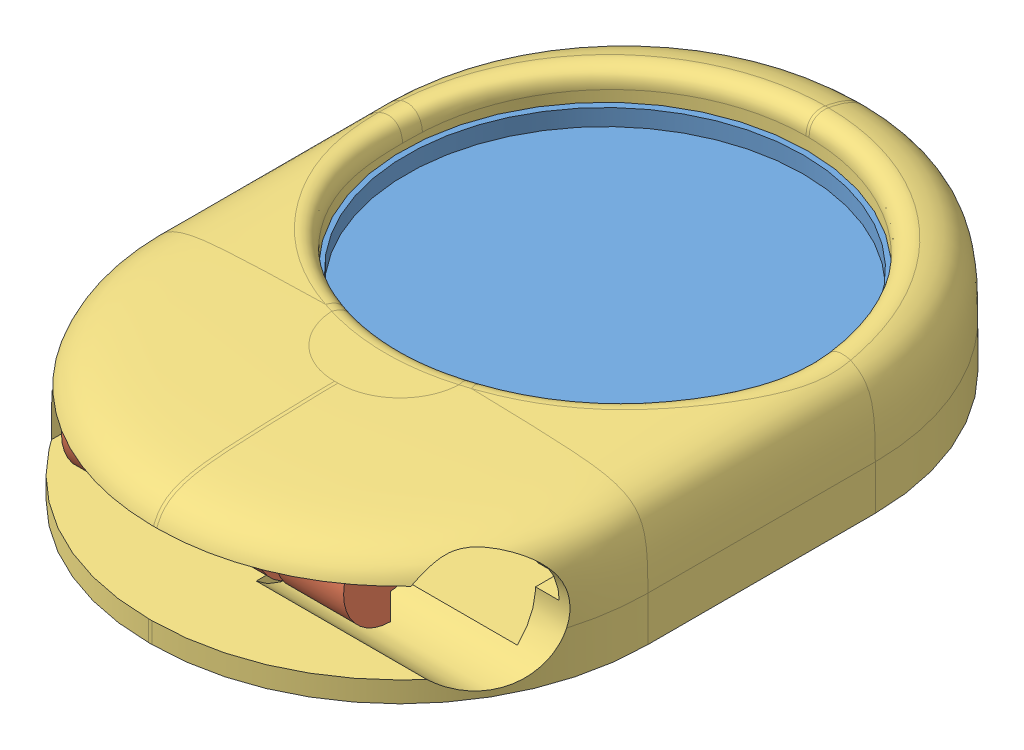
SolidWorks assembly Vibe and speaker enclosure, configuration Default. Lengths in mm.
Overall size (30.69 8.21 44.45).
3 component instances, 3 part files, 5 mates.
Components (placement in the parent):
- Speaker-1: Speaker [Default] at origin size (27.94 4.57 27.94)
- Vibration motor-1: Vibration motor [Default] at (-10.0838 2.4384 20.32) x (0 0 -1) z (0 -1 0) size (6 17.22 6)
- Vibe and speaker enclosure-1: Vibe and speaker enclosure [Default] at origin size (30.69 8.21 44.45)
Mates (geometry in assembly coordinates):
- Coincident1: coincident aligned: plane of Speaker-1 through (0 0 0) normal (1 0 0); plane of assembly through (0 0 0) normal (1 0 0)
- Coincident2: coincident aligned: plane of Speaker-1 through (0 0 0) normal (0 0 1); plane of assembly through (0 0 0) normal (0 0 1)
- Coincident3: coincident aligned: plane of Speaker-1 through (0 0 0) normal (0 1 0); plane of assembly through (0 0 0) normal (0 1 0)
- Concentric1: concentric anti-aligned: cylinder of Vibration motor-1 through (1.8542 2.4384 20.32) axis (-1 0 0) radius 3; cylinder of Vibe and speaker enclosure-1 through (-21.1012 2.4384 20.32) axis (1 0 0) radius 2.9972
- Coincident5: coincident anti-aligned: plane of Vibration motor-1 through (-10.0838 2.4384 20.32) normal (-1 0 0); plane of Vibe and speaker enclosure-1 through (-10.0838 -0.1016 27.94) normal (1 0 0)
